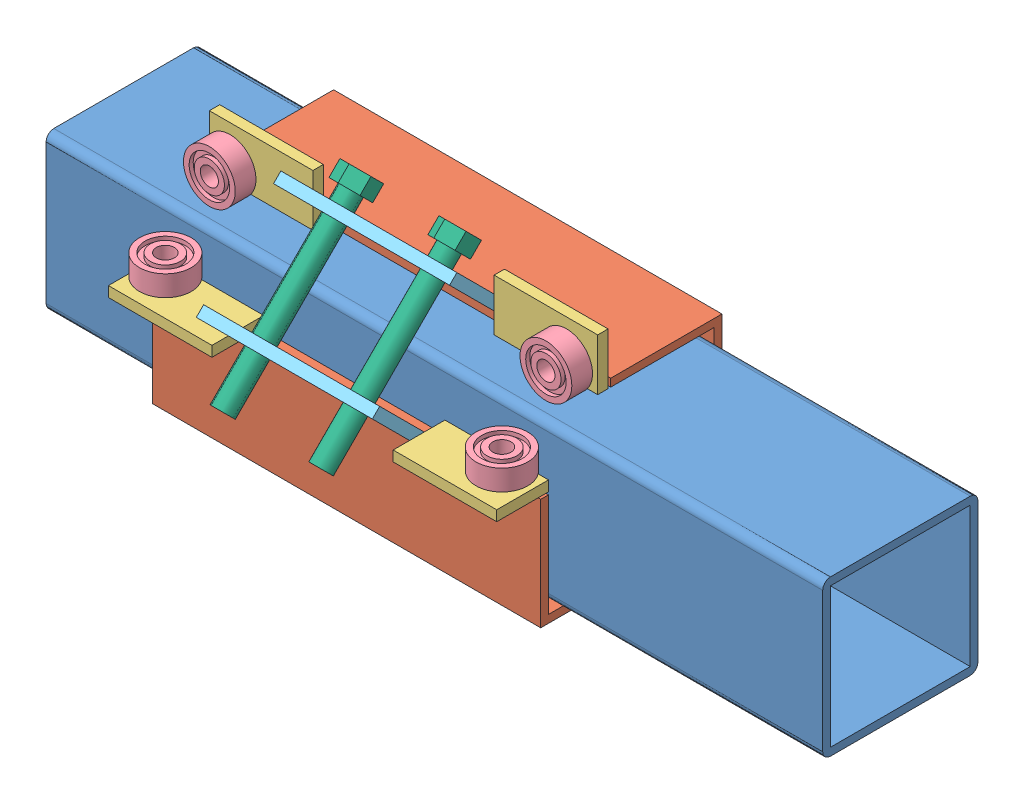
SolidWorks assembly СбНаправляющая, configuration По умолчанию. Lengths in mm.
Overall size (300 164.9 164.9).
29 component instances, 6 part files, 15 mates.
Components (placement in the parent):
- Труба60-1: Труба60 [По умолчанию] at origin size (300 60 60)
- СбКаретка-1: СбКаретка [По умолчанию] at (46.0996 -32 32) size (150 135.07 135.07)
  - Угольник40_150-1: Угольник40_150 [По умолчанию] at origin size (150 43 43)
  - Пластина20_4_150-1: Пластина20_4_150 [По умолчанию] at (150 41 20) x (-1 0 0) z (0 -1 0) size (40 20 4)
  - Пластина20_4_150-3: Пластина20_4_150 [По умолчанию] at (0 45 20) x (1 0 0) z (0 1 0) size (40 20 4)
  - Подшипник20_8_7-1: Подшипник20_8_7 [По умолчанию] at (10 47 8) x (1 0 0) z (0 -1 0) size (20 20 8)
  - Подшипник20_8_7-2: Подшипник20_8_7 [По умолчанию] at (140 47 8) x (1 0 0) z (0 -1 0) size (20 20 8)
  - Пластина20_4_150-4: Пластина20_4_150 [По умолчанию] at (0 -20 -41) size (40 20 4)
  - Пластина20_4_150-5: Пластина20_4_150 [По умолчанию] at (150 -20 -45) x (-1 0 0) z (0 0 -1) size (40 20 4)
  - Подшипник20_8_7-3: Подшипник20_8_7 [По умолчанию] at (140 -8 -47) x (-1 0 0) z (0 0 1) size (20 20 8)
  - Подшипник20_8_7-4: Подшипник20_8_7 [По умолчанию] at (10 -8 -47) x (-1 0 0) z (0 0 1) size (20 20 8)
  - Пластина45-1: Пластина45 [По умолчанию] at (41 58.3848 27.0416) x (1 0 0) z (0 0.707107 0.707107) size (68 4 66.21)
  - Пластина45-2: Пластина45 [По умолчанию] at (41 -24.2132 -61.2132) x (1 0 0) z (0 -0.707107 -0.707107) size (68 4 66.21)
- СбКаретка-2: СбКаретка [По умолчанию] at (46.0996 32 -32) x (1 0 0) z (0 0 -1) size (150 135.07 135.07)
  - Угольник40_150-1: Угольник40_150 [По умолчанию] at origin size (150 43 43)
  - Пластина20_4_150-1: Пластина20_4_150 [По умолчанию] at (150 41 20) x (-1 0 0) z (0 -1 0) size (40 20 4)
  - Пластина20_4_150-3: Пластина20_4_150 [По умолчанию] at (0 45 20) x (1 0 0) z (0 1 0) size (40 20 4)
  - Подшипник20_8_7-1: Подшипник20_8_7 [По умолчанию] at (10 47 8) x (1 0 0) z (0 -1 0) size (20 20 8)
  - Подшипник20_8_7-2: Подшипник20_8_7 [По умолчанию] at (140 47 8) x (1 0 0) z (0 -1 0) size (20 20 8)
  - Пластина20_4_150-4: Пластина20_4_150 [По умолчанию] at (0 -20 -41) size (40 20 4)
  - Пластина20_4_150-5: Пластина20_4_150 [По умолчанию] at (150 -20 -45) x (-1 0 0) z (0 0 -1) size (40 20 4)
  - Подшипник20_8_7-3: Подшипник20_8_7 [По умолчанию] at (140 -8 -47) x (-1 0 0) z (0 0 1) size (20 20 8)
  - Подшипник20_8_7-4: Подшипник20_8_7 [По умолчанию] at (10 -8 -47) x (-1 0 0) z (0 0 1) size (20 20 8)
  - Пластина45-1: Пластина45 [По умолчанию] at (41 58.3848 27.0416) x (1 0 0) z (0 0.707107 0.707107) size (68 4 66.21)
  - Пластина45-2: Пластина45 [По умолчанию] at (41 -24.2132 -61.2132) x (1 0 0) z (0 -0.707107 -0.707107) size (68 4 66.21)
- БолтМ8-1: БолтМ8 [По умолчанию] at (102.0996 54.0919 14.364) x (1 0 0) z (0 0.707107 0.707107) size (12 76 13.86)
- БолтМ8-2: БолтМ8 [По умолчанию] at (102.0996 -14.364 -54.0919) x (1 0 0) z (0 0.707107 0.707107) size (12 76 13.86)
- БолтМ8-3: БолтМ8 [По умолчанию] at (140.0996 54.0919 14.364) x (0.632655 -0.547607 -0.547607) z (0.774433 0.447355 0.447355) size (12 76 13.86)
- БолтМ8-4: БолтМ8 [По умолчанию] at (140.0996 -14.364 -54.0919) x (1 0 0) z (0 0.707107 0.707107) size (12 76 13.86)
Mates (geometry in assembly coordinates):
- Касательность1: tangent anti-aligned: plane of Труба60-1 through (300 -30 27) normal (0 -1 0); cylinder of СбКаретка-1/Подшипник20_8_7-4 through (56.0996 -40 8.3143) axis (0 0 1) radius 10
- Касательность2: tangent anti-aligned: plane of Труба60-1 through (300 27 30) normal (0 0 1); cylinder of СбКаретка-1/Подшипник20_8_7-1 through (56.0996 -8.3143 40) axis (0 -1 0) radius 10
- Параллельность1: parallel anti-aligned: plane of Труба60-1 through (300 27 30) normal (0 0 1); plane of СбКаретка-1/Угольник45_150-1 through (196.0996 8 32) normal (0 0 -1)
- Параллельность2: parallel anti-aligned: plane of Труба60-1 through (300 -30 27) normal (0 -1 0); plane of СбКаретка-1/Угольник45_150-1 through (196.0996 -32 32) normal (0 1 0)
- Касательность6: tangent anti-aligned: plane of Труба60-1 through (300 30 27) normal (0 1 0); cylinder of СбКаретка-2/Подшипник20_8_7-3 through (186.0996 40 -8.3143) axis (0 0 -1) radius 10
- Касательность7: tangent anti-aligned: plane of Труба60-1 through (300 27 -30) normal (0 0 -1); cylinder of СбКаретка-2/Подшипник20_8_7-1 through (56.0996 8.3143 -40) axis (0 1 0) radius 10
- Совпадение5: coincident aligned: plane of СбКаретка-1/Угольник45_150-1 through (46.0996 -32 32) normal (-1 0 0); plane of СбКаретка-2/Угольник45_150-1 through (46.0996 32 -32) normal (-1 0 0)
- Концентричный1: concentric anti-aligned: cylinder of СбКаретка-2/Пластина45-2 through (102.0996 50.5563 17.8995) axis (0 -0.707107 0.707107) radius 4.1; cylinder of БолтМ8-1 through (102.0996 -16.6188 85.0746) axis (0 0.707107 -0.707107) radius 4
- Расстояние3: distance = 5 mm anti-aligned: plane of БолтМ8-1 through (102.0996 54.0919 14.364) normal (0 -0.707107 0.707107); plane of СбКаретка-2/Пластина45-2 through (87.0996 59.0416 26.3848) normal (0 0.707107 -0.707107)
- Концентричный2: concentric aligned: cylinder of СбКаретка-2/Пластина45-1 through (102.0996 -20.7279 -47.7279) axis (0 0.707107 -0.707107) radius 4.1; cylinder of БолтМ8-2 through (102.0996 -85.0746 16.6188) axis (0 0.707107 -0.707107) radius 4
- Совпадение7: coincident aligned: plane of БолтМ8-1 through (102.0996 58.3345 10.1213) normal (0 0.707107 -0.707107); plane of БолтМ8-2 through (102.0996 -10.1213 -58.3345) normal (0 0.707107 -0.707107)
- Концентричный3: concentric anti-aligned: cylinder of СбКаретка-1/Пластина45-1 through (140.0996 20.7279 47.7279) axis (0 -0.707107 0.707107) radius 4.1; cylinder of БолтМ8-3 through (140.0996 -16.6188 85.0746) axis (0 0.707107 -0.707107) radius 4
- Совпадение8: coincident aligned: plane of БолтМ8-1 through (102.0996 58.3345 10.1213) normal (0 0.707107 -0.707107); plane of БолтМ8-3 through (140.0996 58.3345 10.1213) normal (0 0.707107 -0.707107)
- Концентричный4: concentric aligned: cylinder of СбКаретка-2/Пластина45-1 through (140.0996 -20.7279 -47.7279) axis (0 0.707107 -0.707107) radius 4.1; cylinder of БолтМ8-4 through (140.0996 -85.0746 16.6188) axis (0 0.707107 -0.707107) radius 4
- Совпадение9: coincident aligned: plane of БолтМ8-2 through (102.0996 -10.1213 -58.3345) normal (0 0.707107 -0.707107); plane of БолтМ8-4 through (140.0996 -10.1213 -58.3345) normal (0 0.707107 -0.707107)
